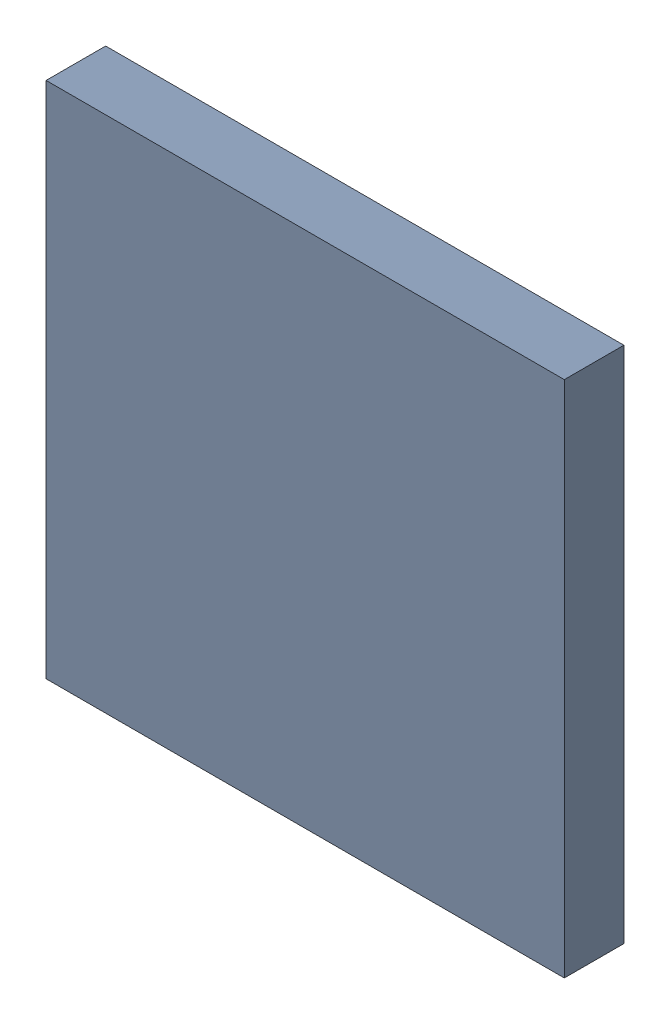
SolidWorks assembly U100_2PCB, configuration Default. Lengths in mm.
Overall size (10 10 1.15).
2 component instances, 1 part files, 0 mates.
Components (placement in the parent):
- 846485464-1: 846485464 [Default] at (106.8 92.2 0.05) size (10 10 1.15)
  - Extruded_42-1: Extruded_42 [Default] at origin size (10 10 1.15)
